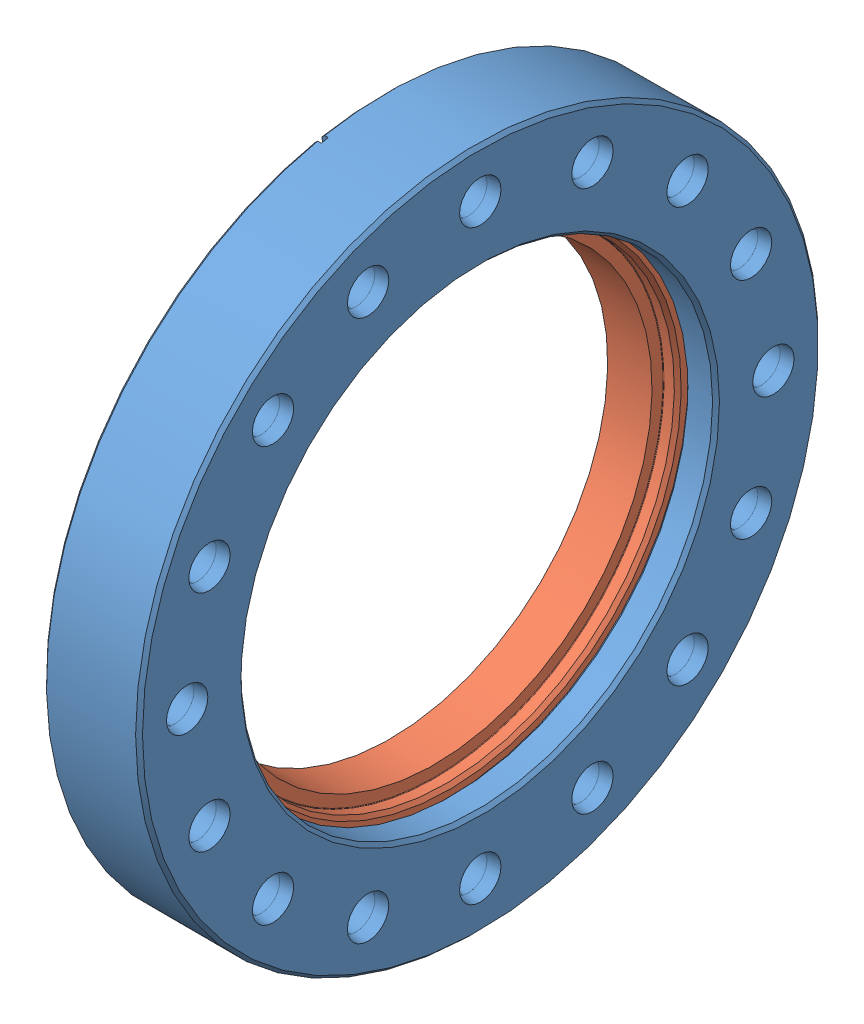
SolidWorks assembly 100026, configuration Default. Lengths in mm.
Overall size (21.34 151.64 151.64).
2 component instances, 2 part files, 2 mates.
Components (placement in the parent):
- 915006-1: 915006 [Default] at (37.6636 72.9454 124.9651) size (21.34 151.64 151.64)
- 910026-1: 910026 [Default] at (38.324 72.9454 124.9651) x (1 0 0) z (0 -0.109256 0.994014) size (13.59 120.42 120.42)
Mates (geometry in assembly coordinates):
- Concentric1: concentric aligned: cylinder of 915006-1 through (37.6636 72.9454 124.9651) axis (-1 0 0) radius 60.325; cylinder of 910026-1 through (38.324 72.9454 124.9651) axis (-1 0 0) radius 60.2107
- Coincident1: coincident anti-aligned: plane of 915006-1 through (51.9638 133.2704 124.9651) normal (-1 0 0); plane of 910026-1 through (51.9638 132.7957 131.5435) normal (1 0 0)
